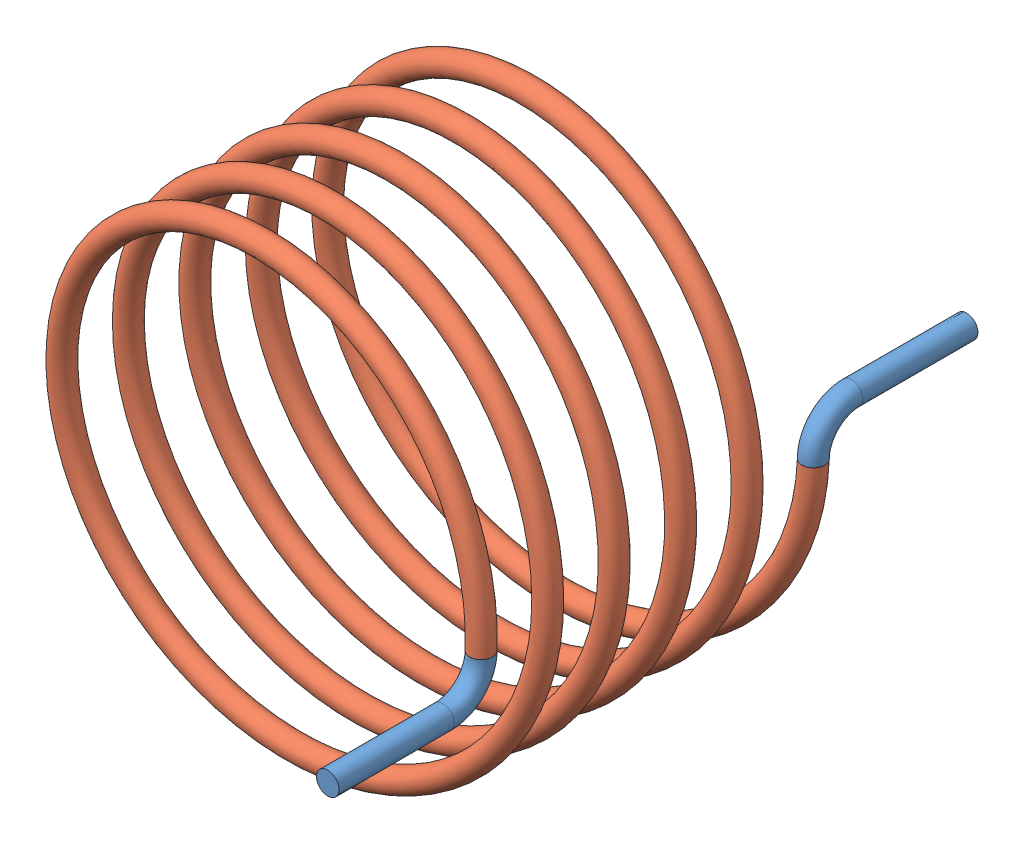
SolidWorks assembly Assem1, configuration Default. Lengths in mm.
Overall size (10.66 10.66 14.34).
3 component instances, 2 part files, 4 mates.
Components (placement in the parent):
- Spring Piece-1: Spring Piece [Default] at (3.4389 -17.0543 9.4121) size (0.51 1.11 3.7)
- Tension Spring-1: Tension Spring [Default] at (-1.6367 -17.0543 1.0902) x (-1 0 0) z (0 0 1) size (10.66 10.66 10.53)
- Spring Piece-2: Spring Piece [Default] at (3.4389 -17.0543 0.2384) x (1 0 0) z (0 0 -1) size (0.51 1.11 3.7)
Mates (geometry in assembly coordinates):
- Coincident7: coincident aligned: circle of Spring Piece-1; circle of Tension Spring-1
- Parallel1: parallel aligned: cylinder of Spring Piece-1 through (3.4389 -17.9112 9.4121) axis (0 0 1) radius 0.254; line of Tension Spring-1 through (-1.6367 -17.8321 8.9339) axis (0 0 1)
- Coincident9: coincident aligned: circle of Tension Spring-1; circle of Spring Piece-2
- Angle3: planar angle = 0 rad aligned: cylinder of Spring Piece-2 through (3.4389 -16.1975 0.2384) axis (0 0 -1) radius 0.254; line of Tension Spring-1 through (-1.6367 -16.2923 1.0902) axis (0 0 -1)
